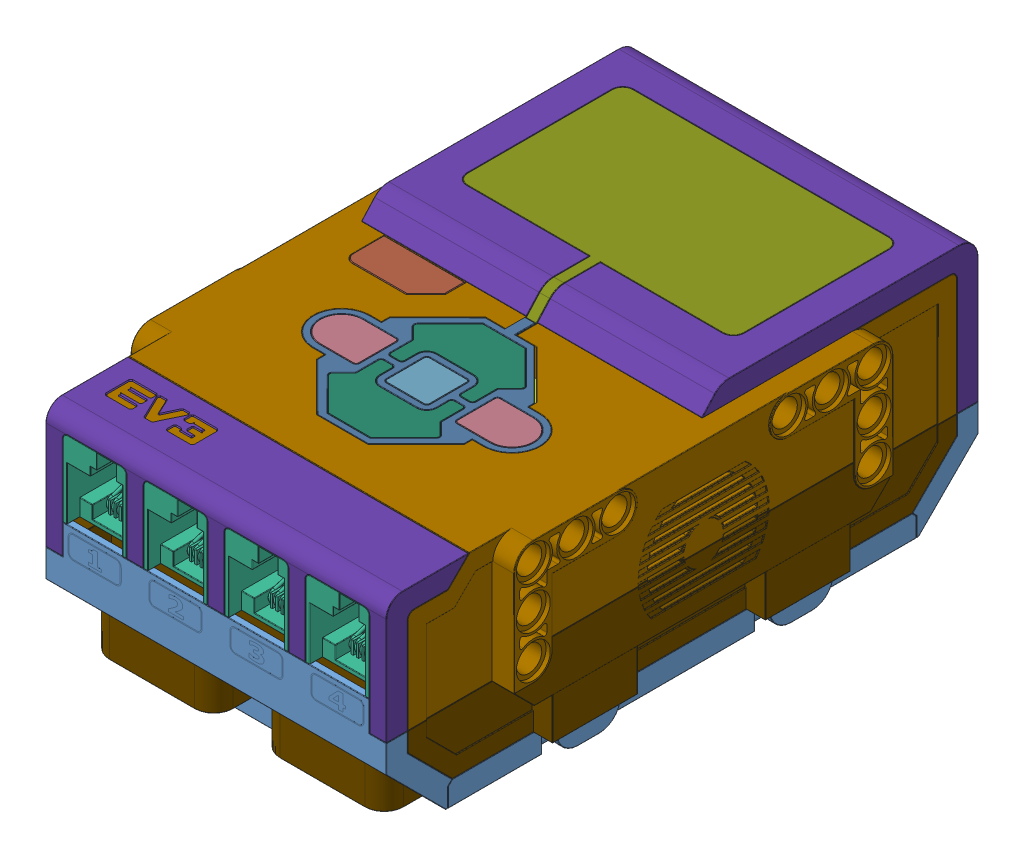
SolidWorks assembly LEGOEV3BRAIN, configuration Default. Lengths in mm.
Overall size (72.13 50.8 111.2).
36 component instances, 25 part files, 0 mates.
Components (placement in the parent):
- 95646c01.stp-1: 95646c01.stp [Default] at origin size (72.13 50.8 111.2)
  - 95656.stp-1: 95656.stp [Default] at (0 -35.2 -16) size (68.8 24 88.8)
    - 11142-LtBluishGray.stp-1: 11142-LtBluishGray.stp [Default] at origin size (68.8 20.8 88.8)
    - 11143-LtBluishGray.stp-1: 11143-LtBluishGray.stp [Default] at (-0.4 -0.4 0) size (50 15.2 87.61)
    - 56554-ElectricAlloy.stp-1: 56554-ElectricAlloy.stp [Default] at (-22.8 4.4 -36) x (0 1 0) z (0 0 1) size (5.6 5.52 5.6)
    - 56555-ElectricAlloy.stp-1: 56555-ElectricAlloy.stp [Default] at (-20.8 4.4 36.4) x (0 0 -1) z (-1 0 0) size (9.6 8.8 0.8)
    - 11177-TransGeen.stp-1: 11177-TransGeen.stp [Default] at (9.6 -8 41.6) x (1 0 0) z (0 -1 0) size (3.2 5.6 3.2)
    - 11177-TransRed.stp-1: 11177-TransRed.stp [Default] at (14.8 -8 41.6) x (1 0 0) z (0 -1 0) size (3.2 5.6 3.2)
    - 11186-Black.stp-1: 11186-Black.stp [Default] at (0 0.8 40) x (0 1 0) z (1 0 0) size (7.2 7.2 4.8)
    - u9208.stp-1: u9208.stp [Default] at (21.6 4.4 36.8) x (1 0 0) z (0 0 -1) size (3.2 8.8 3.2)
    - u9208.stp-2: u9208.stp [Default] at (21.6 4.4 -40) x (1 0 0) z (0 0 -1) size (3.2 8.8 3.2)
    - u9208.stp-3: u9208.stp [Default] at (21.6 4.4 0) x (1 0 0) z (0 0 -1) size (3.2 8.8 3.2)
    - u9208.stp-4: u9208.stp [Default] at (-20.8 4.4 28) x (1 0 0) z (0 0 -1) size (3.2 8.8 3.2)
    - u9208.stp-5: u9208.stp [Default] at (-20.8 4.4 -27.6) x (1 0 0) z (0 0 -1) size (3.2 8.8 3.2)
  - 99141p01-White.stp-1: 99141p01-White.stp [Default] at origin size (72.13 26.01 104.41)
  - 11026-TransClear.stp-1: 11026-TransClear.stp [Default] at (0 -2.6 0) size (42.56 5.2 35.4)
  - 11030-LtBluishGray.stp-1: 11030-LtBluishGray.stp [Default] at (-20 -2.5473 -15.88) size (15.28 5.2 7.44)
  - 11036-LCD.stp-1: 11036-LCD.stp [Default] at (0 1.999 -45.7343) size (52 1.6 40)
  - 99145-LtBluishGray.stp-1: 99145-LtBluishGray.stp [Default] at (-16 -2.6 0) size (10.88 5.2 8.16)
  - 99145-LtBluishGray.stp-2: 99145-LtBluishGray.stp [Default] at (16 -2.6 0) x (-1 0 0) z (0 0 -1) size (10.88 5.2 8.16)
  - 99146-LtBluishGray.stp-1: 99146-LtBluishGray.stp [Default] at (0 -2.6 0) size (8.16 5.2 8.16)
  - 99147-LtBluishGray.stp-1: 99147-LtBluishGray.stp [Default] at (0 -2.6 7.98) x (-1 0 0) z (0 0 -1) size (20.74 5.2 14)
  - 99147-LtBluishGray.stp-2: 99147-LtBluishGray.stp [Default] at (0 -2.6 -7.98) size (20.74 5.2 14)
  - 99148p01-TransClear.stp-1: 99148p01-TransClear.stp [Default] at (0 2.8 -47.2) size (52 8 43.2)
  - 99141s01-LtBluishGray.stp-1: 99141s01-LtBluishGray.stp [Default] at (0 0 2.2) size (64 27.2 111.2)
  - 11025-White.stp-1: 11025-White.stp [Default] at (0 -26.8 -16) size (71.6 22 103.2)
  - 11025s02-LtBluishGray.stp-1: 11025s02-LtBluishGray.stp [Default] at (0 -23.2 -16) size (64 22 111.2)
  - 11032-Black.stp-1: 11032-Black.stp [Default] at (-27.6 -14.6 -32) x (0 0 1) z (-1 0 0) size (14.4 6 14.4)
  - 11033-Black.stp-1: 11033-Black.stp [Default] at (23.2 -15.6 -68.8) x (-1 0 0) z (0 0 -1) size (8.2 4.2 10)
  - 11034-Black.stp-1: 11034-Black.stp [Default] at (-34.8 -16.6 -12) x (0 0 1) z (-1 0 0) size (14.4 2 15.2)
  - 11035-LtBluishGray.stp-1: 11035-LtBluishGray.stp [Default] at (-6 -10.8 -71.6) x (-1 0 0) z (0 0 -1) size (45.6 14.56 14.4)
  - 54732b-LtBluishGray.stp-1: 54732b-LtBluishGray.stp [Default] at (-22.8 -10.8 39.6) size (12 14.56 14.4)
  - 54732b-LtBluishGray.stp-2: 54732b-LtBluishGray.stp [Default] at (-7.6 -10.8 39.6) size (12 14.56 14.4)
  - 54732b-LtBluishGray.stp-3: 54732b-LtBluishGray.stp [Default] at (7.6 -10.8 39.6) size (12 14.56 14.4)
  - 54732b-LtBluishGray.stp-4: 54732b-LtBluishGray.stp [Default] at (22.8 -10.8 39.6) size (12 14.56 14.4)
  - 97622-PCB.stp-1: 97622-PCB.stp [Default] at (0 -6 0) size (48 1.6 40)
